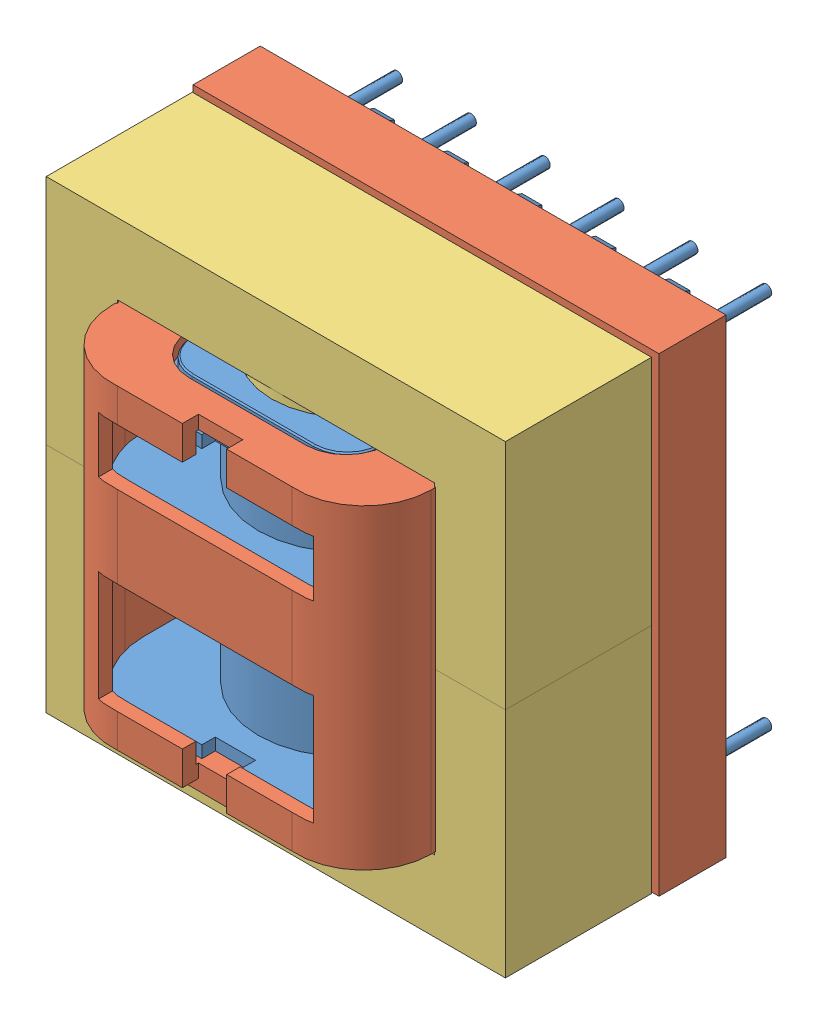
SolidWorks assembly XFMR, configuration Default. Lengths in mm.
Overall size (34.7 35 28.12).
4 component instances, 3 part files, 0 mates.
Components (placement in the parent):
- Bobbin_ETD34-1: Bobbin_ETD34 [Default] at origin size (32 32.5 26.8)
- Cover_ETD34-1: Cover_ETD34 [Default] at (0 0 -10.75) x (0 1 0) z (0 0 1) size (35 34.7 21.52)
- Core_ETD34-1: Core_ETD34 [Default] at (0 -17.3 0) x (-1 0 0) z (0 0 1) size (34.2 17.3 10.88)
- Core_ETD34-2: Core_ETD34 [Default] at (0 17.3 0) x (-1 0 0) z (0 0 -1) size (34.2 17.3 10.88)
